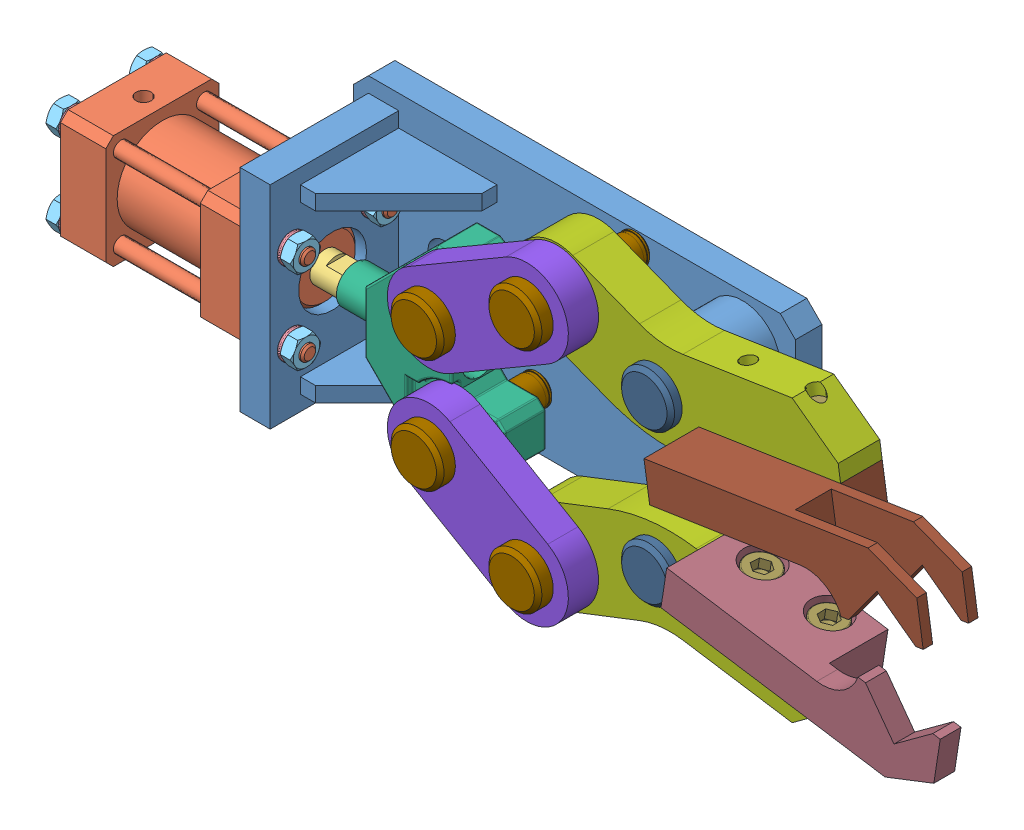
SolidWorks assembly Assemblage, configuration Défaut. Lengths in mm.
Overall size (238.31 105.35 47).
37 component instances, 13 part files, 36 mates.
Components (placement in the parent):
- assemblage pince-1: assemblage pince [Défaut] at (41.4784 14.1991 146.5) size (167 64 41)
  - Corps-1: Corps [Défaut] at origin size (117 64 41)
  - Corps verin-1: Corps verin [Défaut] at (-85 -15 9.5) x (0 0 1) z (-1 0 0) size (30 30 67)
  - Tige verin-1: Tige verin [Défaut] at (-69 0 24.5) x (0 1 0) z (-1 0 0) size (20 20 53)
  - rondelle w4-1: rondelle w4 [Default] at (-76.1 -11 13.5) size (0.93 7.55 7.56)
  - rondelle w4-2: rondelle w4 [Default] at (-76.1 -11 35.5) size (0.93 7.55 7.56)
  - rondelle w4-3: rondelle w4 [Default] at (-76.1 11 13.5) size (0.93 7.55 7.56)
  - rondelle w4-4: rondelle w4 [Default] at (-76.1 11 35.5) size (0.93 7.55 7.56)
  - rondelle w4-5: rondelle w4 [Default] at (-134 -11 13.5) size (0.93 7.55 7.56)
  - rondelle w4-6: rondelle w4 [Default] at (-134 -11 35.5) size (0.93 7.55 7.56)
  - rondelle w4-7: rondelle w4 [Default] at (-134 11 35.5) size (0.93 7.55 7.56)
  - rondelle w4-8: rondelle w4 [Default] at (-134 11 13.5) size (0.93 7.55 7.56)
  - Ecrou H M4-1: Ecrou H M4 [Default] at (-72.9 11 35.5) x (0 0.5 -0.866025) z (1 0 0) size (7 8.08 3.2)
  - Ecrou H M4-2: Ecrou H M4 [Default] at (-72.9 11 13.5) x (0 1 0) z (1 0 0) size (7 8.08 3.2)
  - Ecrou H M4-3: Ecrou H M4 [Default] at (-72.9 -11 35.5) x (0 0.5 -0.866025) z (1 0 0) size (7 8.08 3.2)
  - Ecrou H M4-4: Ecrou H M4 [Default] at (-72.9 -11 13.5) x (0 1 0) z (1 0 0) size (7 8.08 3.2)
  - Ecrou H M4-5: Ecrou H M4 [Default] at (-138.1 11 13.5) x (0 0.5 0.866025) z (-1 0 0) size (7 8.08 3.2)
  - Ecrou H M4-6: Ecrou H M4 [Default] at (-138.1 11 35.5) x (0 0.5 0.866025) z (-1 0 0) size (7 8.08 3.2)
  - Ecrou H M4-7: Ecrou H M4 [Default] at (-134.9 -11 35.5) x (0 -0.5 -0.866025) z (1 0 0) size (7 8.08 3.2)
  - Ecrou H M4-8: Ecrou H M4 [Default] at (-138.1 -11 13.5) x (0 0.5 0.866025) z (-1 0 0) size (7 8.08 3.2)
  - Embout de verin-1: Embout de verin [Défaut] at (-56 25 24.5) x (1 0 0) z (0 -1 0) size (45 15 50)
- Porte machoire-1: Porte machoire [Défaut] at (44.6917 12.2982 165.5) x (0.988306 0.152481 0) z (0 0 1) size (84.75 37 11)
- Pièce1-1: Pièce1 [Défaut] at (-2.0725 38.6958 176.5) x (0.504628 -0.863337 0) z (0 0 1) size (22 52 8)
- Axe de biellette-1: Axe de biellette [Défaut] at (21.4902 47.4731 149.5488) x (-0.929292 0.369345 0) z (0 0 1) size (14 14 33)
- Axe de biellette-2: Axe de biellette [Défaut] at (11.967 29.1991 149.5488) size (14 14 33)
- Axe de porte machoire-1: Axe de porte machoire [Défaut] at (68.1592 34.1991 135.9008) size (14 14 35.5)
- Porte machoire-2: Porte machoire [Défaut] at (44.6917 16.0999 176.5) x (0.988306 -0.152481 0) z (0 0 -1) size (84.75 37 11)
- Pièce1-2: Pièce1 [Défaut] at (9.0293 8.6958 176.5) x (-0.504628 -0.863337 0) z (0 0 1) size (22 52 8)
- Axe de biellette-3: Axe de biellette [Défaut] at (11.967 -0.8009 149.5488) size (14 14 33)
- Axe de biellette-4: Axe de biellette [Défaut] at (37.8671 -15.9398 149.5488) size (14 14 33)
- Axe de porte machoire-2: Axe de porte machoire [Défaut] at (68.1592 -5.8009 135.9008) size (14 14 35.5)
- Machoire gauche-1: Machoire gauche [Défaut] at (68.4083 22.5342 165.5) x (0.988306 0.152481 0) z (0 0 1) size (72 18 25.5)
- Vis Chc M5x16-1: Vis Chc M5x16 [ISO 4762 M5 x 16 --- 16N] at (95.9284 27.792 171) x (-0.152481 0.988306 0) z (-0.987656 -0.15238 -0.03628) size (21 8.5 8.5)
- Vis Chc M5x16-2: Vis Chc M5x16 [ISO 4762 M5 x 16 --- 16N] at (78.1389 25.0473 171) x (-0.152481 0.988306 0) z (0.395329 0.060993 0.916512) size (21 8.5 8.5)
- Machoire droite-1: Machoire droite [Défaut] at (68.4083 5.8639 186.5) x (0.988306 -0.152481 0) z (0 0 -1) size (72 18 21)
- Vis Chc M5x16-3: Vis Chc M5x16 [ISO 4762 M5 x 16 --- 16N] at (95.9284 0.6062 171) x (-0.152481 -0.988306 0) z (0.514812 -0.079428 0.853615) size (21 8.5 8.5)
- Vis Chc M5x16-4: Vis Chc M5x16 [ISO 4762 M5 x 16 --- 16N] at (78.1389 3.3508 171) x (-0.152481 -0.988306 0) z (-0.987131 0.152299 -0.048748) size (21 8.5 8.5)
Mates (geometry in assembly coordinates):
- Coaxiale1: concentric aligned: cylinder of assemblage pince-1/Corps-1 through (55.4784 34.1991 146.5) axis (0 0 1) radius 4; cylinder of Porte machoire-1 through (55.4784 34.1991 165.5) axis (0 0 1) radius 4
- Coaxiale3: concentric aligned: cylinder of assemblage pince-1/Embout de verin-1 through (3.4784 29.1991 163.5) axis (0 0 1) radius 4; cylinder of Pièce1-1 through (3.4784 29.1991 176.5) axis (0 0 1) radius 4
- Coïncidente2: coincident anti-aligned: plane of assemblage pince-1/Embout de verin-1 through (-8.5216 -10.8009 176.5) normal (0 0 1); plane of Pièce1-1 through (3.4784 29.1991 176.5) normal (0 0 -1)
- Coïncidente3: coincident anti-aligned: plane of Porte machoire-1 through (59.2764 68.9947 176.5) normal (0 0 1); plane of Pièce1-1 through (3.4784 29.1991 176.5) normal (0 0 -1)
- Coaxiale8: concentric aligned: cylinder of Porte machoire-1 through (29.3785 44.3379 165.5) axis (0 0 1) radius 4; cylinder of Pièce1-1 through (29.3785 44.3379 176.5) axis (0 0 1) radius 4
- Coaxiale9: concentric aligned: cylinder of Pièce1-1 through (29.3785 44.3379 176.5) axis (0 0 1) radius 4; cylinder of Axe de biellette-1 through (29.3785 44.3379 205.8422) axis (0 0 1) radius 4
- Coïncidente5: coincident anti-aligned: plane of Pièce1-1 through (3.4784 29.1991 184.5) normal (0 0 1); plane of Axe de biellette-1 through (33.0957 42.8605 184.5) normal (0 0 -1)
- Coaxiale10: concentric aligned: cylinder of Pièce1-1 through (3.4784 29.1991 176.5) axis (0 0 1) radius 4; cylinder of Axe de biellette-2 through (3.4784 29.1991 205.8422) axis (0 0 1) radius 4
- Coïncidente6: coincident anti-aligned: plane of Pièce1-1 through (3.4784 29.1991 184.5) normal (0 0 1); plane of Axe de biellette-2 through (-0.5216 29.1991 184.5) normal (0 0 -1)
- Coaxiale11: concentric aligned: cylinder of Porte machoire-1 through (55.4784 34.1991 165.5) axis (0 0 1) radius 4; cylinder of Axe de porte machoire-1 through (55.4784 34.1991 203.4388) axis (0 0 1) radius 4
- Coïncidente7: coincident anti-aligned: plane of Porte machoire-1 through (59.2764 68.9947 176.5) normal (0 0 1); plane of Axe de porte machoire-1 through (51.4784 34.1991 176.5) normal (0 0 -1)
- Coaxiale12: concentric anti-aligned: cylinder of assemblage pince-1/Corps-1 through (55.4784 -5.8009 146.5) axis (0 0 1) radius 4; cylinder of Porte machoire-2 through (55.4784 -5.8009 176.5) axis (0 0 -1) radius 4
- Coïncidente8: coincident anti-aligned: plane of assemblage pince-1/Corps-1 through (55.4784 -5.8009 165.5) normal (0 0 1); plane of Porte machoire-2 through (59.2764 -40.5965 165.5) normal (0 0 -1)
- Coaxiale13: concentric aligned: cylinder of assemblage pince-1/Embout de verin-1 through (3.4784 -0.8009 163.5) axis (0 0 1) radius 4; cylinder of Pièce1-2 through (3.4784 -0.8009 176.5) axis (0 0 1) radius 4
- Coïncidente9: coincident anti-aligned: plane of assemblage pince-1/Embout de verin-1 through (-8.5216 -10.8009 176.5) normal (0 0 1); plane of Pièce1-2 through (3.4784 -0.8009 176.5) normal (0 0 -1)
- Coaxiale14: concentric anti-aligned: cylinder of Porte machoire-2 through (29.3785 -15.9398 176.5) axis (0 0 -1) radius 4; cylinder of Pièce1-2 through (29.3785 -15.9398 176.5) axis (0 0 1) radius 4
- Coaxiale15: concentric aligned: cylinder of Pièce1-2 through (3.4784 -0.8009 176.5) axis (0 0 1) radius 4; cylinder of Axe de biellette-3 through (3.4784 -0.8009 205.8422) axis (0 0 1) radius 4
- Coïncidente10: coincident anti-aligned: plane of Pièce1-2 through (3.4784 -0.8009 184.5) normal (0 0 1); plane of Axe de biellette-3 through (-0.5216 -0.8009 184.5) normal (0 0 -1)
- Coaxiale16: concentric aligned: cylinder of Pièce1-2 through (29.3785 -15.9398 176.5) axis (0 0 1) radius 4; cylinder of Axe de biellette-4 through (29.3785 -15.9398 205.8422) axis (0 0 1) radius 4
- Coïncidente11: coincident anti-aligned: plane of Pièce1-2 through (3.4784 -0.8009 184.5) normal (0 0 1); plane of Axe de biellette-4 through (25.3785 -15.9398 184.5) normal (0 0 -1)
- Coaxiale17: concentric anti-aligned: cylinder of Porte machoire-2 through (55.4784 -5.8009 176.5) axis (0 0 -1) radius 4; cylinder of Axe de porte machoire-2 through (55.4784 -5.8009 203.4388) axis (0 0 1) radius 4
- Coïncidente12: coincident anti-aligned: plane of Porte machoire-2 through (59.2764 -40.5965 176.5) normal (0 0 1); plane of Axe de porte machoire-2 through (51.4784 -5.8009 176.5) normal (0 0 -1)
- Coaxiale18: concentric aligned: cylinder of Porte machoire-1 through (91.2245 58.2805 171) axis (0.152481 -0.988306 0) radius 2; cylinder of Machoire gauche-1 through (94.2511 38.6634 171) axis (0.152481 -0.988306 0) radius 2.75
- Coaxiale19: concentric aligned: cylinder of Porte machoire-1 through (73.4349 55.5358 171) axis (0.152481 -0.988306 0) radius 2; cylinder of Machoire gauche-1 through (76.4616 35.9187 171) axis (0.152481 -0.988306 0) radius 2.75
- Coïncidente13: coincident anti-aligned: plane of Porte machoire-1 through (66.8835 32.4173 176.5) normal (0.152481 -0.988306 0); plane of Machoire gauche-1 through (66.8835 32.4173 191) normal (-0.152481 0.988306 0)
- Coaxiale20: concentric aligned: cylinder of Machoire gauche-1 through (94.2511 38.6634 171) axis (0.152481 -0.988306 0) radius 2.75; cylinder of Vis Chc M5x16-1 through (100.7696 -3.5867 171) axis (0.152481 -0.988306 0) radius 2.5
- Coïncidente14: coincident anti-aligned: plane of Machoire gauche-1 through (95.166 32.7335 171) normal (0.152481 -0.988306 0); plane of Vis Chc M5x16-1 through (95.3184 32.757 166.7528) normal (-0.152481 0.988306 0)
- Coaxiale21: concentric aligned: cylinder of Machoire gauche-1 through (76.4616 35.9187 171) axis (0.152481 -0.988306 0) radius 2.75; cylinder of Vis Chc M5x16-2 through (82.9801 -6.3314 171) axis (0.152481 -0.988306 0) radius 2.5
- Coïncidente15: coincident anti-aligned: plane of Machoire gauche-1 through (77.3765 29.9889 171) normal (0.152481 -0.988306 0); plane of Vis Chc M5x16-2 through (73.5268 29.3949 172.7) normal (-0.152481 0.988306 0)
- Coaxiale22: concentric aligned: cylinder of Porte machoire-2 through (73.4349 -27.1377 171) axis (0.152481 0.988306 0) radius 2; cylinder of Machoire droite-1 through (76.4616 -7.5206 171) axis (0.152481 0.988306 0) radius 2.75
- Coaxiale23: concentric aligned: cylinder of Porte machoire-2 through (91.2245 -29.8823 171) axis (0.152481 0.988306 0) radius 2; cylinder of Machoire droite-1 through (94.2511 -10.2652 171) axis (0.152481 0.988306 0) radius 2.75
- Coïncidente16: coincident anti-aligned: plane of Porte machoire-2 through (66.8835 -4.0191 165.5) normal (0.152481 0.988306 0); plane of Machoire droite-1 through (66.8835 -4.0191 165.5) normal (-0.152481 -0.988306 0)
- Coaxiale24: concentric aligned: cylinder of Machoire droite-1 through (94.2511 -10.2652 171) axis (0.152481 0.988306 0) radius 2.75; cylinder of Vis Chc M5x16-3 through (100.7696 31.9849 171) axis (0.152481 0.988306 0) radius 2.5
- Coïncidente17: coincident anti-aligned: plane of Machoire droite-1 through (95.166 -4.3354 171) normal (0.152481 0.988306 0); plane of Vis Chc M5x16-3 through (98.7514 -4.8886 168.7862) normal (-0.152481 -0.988306 0)
- Coaxiale25: concentric aligned: cylinder of Machoire droite-1 through (76.4616 -7.5206 171) axis (0.152481 0.988306 0) radius 2.75; cylinder of Vis Chc M5x16-4 through (82.9801 34.7295 171) axis (0.152481 0.988306 0) radius 2.5
- Coïncidente18: coincident anti-aligned: plane of Machoire droite-1 through (77.3765 -1.5907 171) normal (0.152481 0.988306 0); plane of Vis Chc M5x16-4 through (77.1717 -1.5591 175.2449) normal (-0.152481 -0.988306 0)
